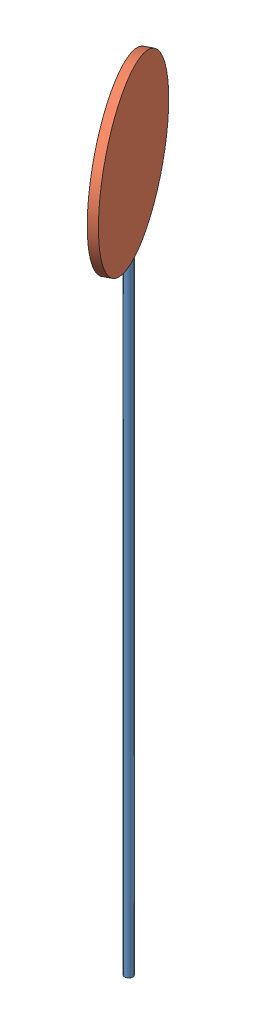
SolidWorks assembly Assem1, configuration Default. Lengths in mm.
Overall size (209.3 1906.85 376.6).
2 component instances, 2 part files, 3 mates.
Components (placement in the parent):
- Pole-1: Pole [Default] at (243.3466 -98.2392 1407.4383) size (20 1500 20)
- sign-1: sign [Default] at (251.6889 1601.458 1404.218) x (0.016838 0.999337 0.032289) z (-0.886685 0 0.462373) size (400 400 20)
Mates (geometry in assembly coordinates):
- Tangent5: tangent: circle of Pole-1; cylinder of sign-1 through (233.9552 1601.458 1413.4655) axis (0.886685 0 -0.462373) radius 200
- Perpendicular3: perpendicular: plane of Pole-1 through (243.3466 1401.7608 1407.4383) normal (0 1 0); plane of sign-1 through (233.9552 1601.458 1413.4655) normal (-0.886685 0 0.462373)
- Lock1: lock: unknown of Pole-1; unknown of sign-1
